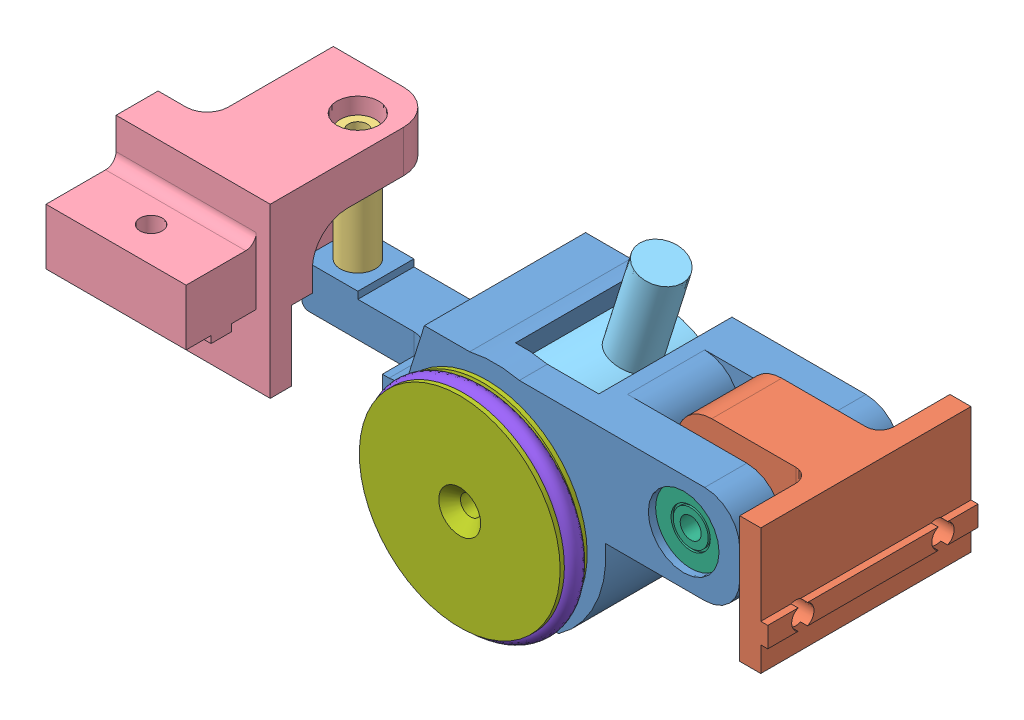
SolidWorks assembly AssemblageBigRobotEncoderWithSupportBlock, configuration Default. Lengths in mm.
Overall size (90 46.93 43).
10 component instances, 9 part files, 17 mates.
Components (placement in the parent):
- Support-BigRobot-Coders-Scancon-2RMHF-1: Support-BigRobot-Coders-Scancon-2RMHF [Défaut] at (-55.8471 14.2764 16.8774) size (70 28.9 23.27)
- Support-BigRobot-Coders-Pivot-MakerBeam-1: Support-BigRobot-Coders-Pivot-MakerBeam [Default] at (-25.8471 18.7764 1.3774) size (23 18 30)
- Support-BigRobot-Coders-Spring-Cylinder-1: Support-BigRobot-Coders-Spring-Cylinder [Default] at (-86.8471 37.7764 16.8774) x (1 0 0) z (0 -1 0) size (5 5 16)
- Support-BigRobot-Coders-Pivot-Opposite-MakerBeam-1: Support-BigRobot-Coders-Pivot-Opposite-MakerBeam [Default] at (-81.8471 27.7764 22.3774) x (0 0 1) z (-1 0 0) size (34 24 22)
- Coders-Scancon-2RMHF-1: Coders-Scancon-2RMHF [Défaut] at (-55.8471 14.2764 5.0774) x (0 0 1) z (-0.95391 0.300092 0) size (24.4 36.85 23.7)
- Pièce3^AssemblageBigRobotEncoderWithSupportBlock-1: Pièce3^AssemblageBigRobotEncoderWithSupportBlock [Default] at origin (virtual)
- Bearing13mm_3mm_5mmWidth-1: Bearing13mm_3mm_5mmWidth [Default] at (-28.8471 22.7764 22.3774) size (13 13 5)
- Bearing13mm_3mm_5mmWidth-2: Bearing13mm_3mm_5mmWidth [Default] at (-28.8471 22.7764 6.3774) size (13 13 5)
- Wheel-Free-27x5mm-1: Wheel-Free-27x5mm [Défaut] at (-55.8471 14.2764 31.4074) x (0.492695 0.870202 0) z (-0.870202 0.492695 0) size (28.66 4.46 28.66)
- Wheel-Free-27x5mm-Rubber-1: Wheel-Free-27x5mm-Rubber [Défaut] at (-56.0363 13.583 31.2052) x (-0.975461 0.219582 0.016103) z (-0.219531 -0.975593 0.00486) size (30.24 2.62 30.24)
Mates (geometry in assembly coordinates):
- Coïncidente1: coincident anti-aligned: plane of Support-BigRobot-Coders-Scancon-2RMHF-1 through (-90.8471 21.7764 28.6509) normal (0 1 0); plane of Support-BigRobot-Coders-Spring-Cylinder-1 through (-86.8471 21.7764 16.8774) normal (0 -1 0)
- Coaxiale1: concentric anti-aligned: cylinder of Support-BigRobot-Coders-Scancon-2RMHF-1 through (-86.8471 -1.6236 16.8774) axis (0 1 0) radius 1.5; circle of Support-BigRobot-Coders-Spring-Cylinder-1
- Coaxiale2: concentric aligned: cylinder of Support-BigRobot-Coders-Spring-Cylinder-1 through (-86.8471 21.7764 16.8774) axis (0 1 0) radius 2.5; cylinder of Support-BigRobot-Coders-Pivot-Opposite-MakerBeam-1 through (-86.8471 15.7764 16.8774) axis (0 1 0) radius 3
- Parallèle1: parallel aligned: plane of Support-BigRobot-Coders-Scancon-2RMHF-1 through (-71.8471 -4.6503 20.8774) normal (0 0 1); plane of Support-BigRobot-Coders-Pivot-Opposite-MakerBeam-1 through (-103.8471 15.7764 34.3774) normal (0 0 1)
- Coïncidente3: coincident anti-aligned: plane of Support-BigRobot-Coders-Scancon-2RMHF-1 through (-55.8471 14.2764 24.3774) normal (0 0 -1); plane of Coders-Scancon-2RMHF-1 through (-53.8065 20.7629 24.3774) normal (0 0 1)
- Coaxiale3: concentric aligned: circle of Support-BigRobot-Coders-Scancon-2RMHF-1; circle of Coders-Scancon-2RMHF-1
- Coaxiale4: concentric aligned: circle of Support-BigRobot-Coders-Scancon-2RMHF-1; cylinder of Coders-Scancon-2RMHF-1 through (-46.5736 16.3385 20.3774) axis (0 0 1) radius 1
- Coaxiale6: concentric anti-aligned: cylinder of Support-BigRobot-Coders-Scancon-2RMHF-1 through (-28.8471 22.7764 5.3774) axis (0 0 1) radius 5.05; cylinder of Bearing13mm_3mm_5mmWidth-1 through (-28.8471 22.7764 27.3774) axis (0 0 -1) radius 6.5
- Coïncidente5: coincident aligned: plane of Support-BigRobot-Coders-Scancon-2RMHF-1 through (-37.8471 -1.6236 22.3774) normal (0 0 -1); plane of Bearing13mm_3mm_5mmWidth-1 through (-28.8471 22.7764 22.3774) normal (0 0 -1)
- Coaxiale7: concentric anti-aligned: cylinder of Support-BigRobot-Coders-Scancon-2RMHF-1 through (-28.8471 22.7764 5.3774) axis (0 0 1) radius 5.05; cylinder of Bearing13mm_3mm_5mmWidth-2 through (-28.8471 22.7764 11.3774) axis (0 0 -1) radius 6.5
- Coïncidente6: coincident aligned: plane of Support-BigRobot-Coders-Scancon-2RMHF-1 through (-37.8471 -1.6236 11.3774) normal (0 0 1); plane of Bearing13mm_3mm_5mmWidth-2 through (-28.8471 22.7764 11.3774) normal (0 0 1)
- Distance1: distance = 0.5 mm anti-aligned: plane of Support-BigRobot-Coders-Pivot-MakerBeam-1 through (-28.8471 22.7764 21.8774) normal (0 0 1); plane of Bearing13mm_3mm_5mmWidth-1 through (-28.8471 22.7764 22.3774) normal (0 0 -1)
- Coïncidente9: coincident aligned: plane of Support-BigRobot-Coders-Scancon-2RMHF-1 through (-20.8471 15.7764 28.3774) normal (0 -1 0); plane of Support-BigRobot-Coders-Pivot-Opposite-MakerBeam-1 through (-103.8471 15.7764 10.3774) normal (0 -1 0)
- Coaxiale11: concentric anti-aligned: circle of Support-BigRobot-Coders-Pivot-MakerBeam-1; circle of Bearing13mm_3mm_5mmWidth-2
- Parallèle4: parallel aligned: plane of Support-BigRobot-Coders-Scancon-2RMHF-1 through (-20.8471 29.7764 28.3774) normal (0 1 0); plane of Support-BigRobot-Coders-Pivot-MakerBeam-1 through (-36.8471 31.7764 31.3774) normal (0 1 0)
- Coaxiale12: concentric: cylinder of Coders-Scancon-2RMHF-1 through (-55.8471 14.2764 15.4774) axis (0 0 1) radius 2; cylinder of Wheel-Free-27x5mm-1 through (-55.8471 14.2764 13.4274) axis (0 0 -1) radius 3.15
- Coïncidente11: coincident anti-aligned: plane of Coders-Scancon-2RMHF-1 through (-55.8471 14.2764 29.4774) normal (0 0 1); plane of Wheel-Free-27x5mm-1 through (-55.1327 15.5381 29.4774) normal (0 0 -1)
